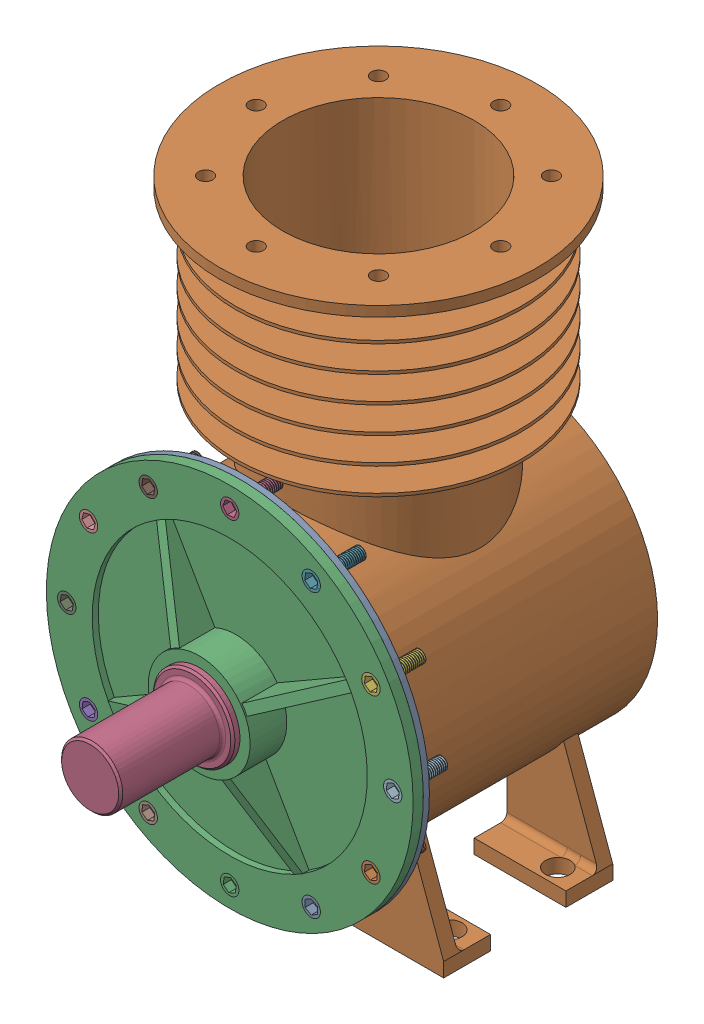
SolidWorks assembly montaj, configuration Varsayılan. Lengths in mm.
Overall size (245.88 307.94 235).
18 component instances, 7 part files, 38 mates.
Components (placement in the parent):
- motor gövdesi-1: motor gövdesi [Varsayılan] at (-13.4199 -2.0149 0) size (180 282 171.5)
- motor kapağı-1: motor kapağı [Varsayılan] at (-13.4199 -2.0149 0) x (-0.866025 -0.5 0) z (0 0 -1) size (180 180 23)
- M6 cıvata-1: M6 cıvata [Varsayılan] at (-13.4199 77.9851 -16) x (0 0 -1) z (0.93131 -0.364228 0) size (24 9 9)
- M6 cıvata-2: M6 cıvata [Varsayılan] at (-82.7019 -42.0149 -16) x (0 0 -1) z (0.991988 -0.126329 0) size (24 9 9)
- M6 cıvata-3: M6 cıvata [Varsayılan] at (55.8621 37.9851 -16) x (0 0 -1) z (0.993619 -0.112785 0) size (24 9 9)
- M6 cıvata-4: M6 cıvata [Varsayılan] at (26.5801 67.2671 -16) x (0 0 -1) z (0.991629 -0.129118 0) size (24 9 9)
- M6 cıvata-5: M6 cıvata [Varsayılan] at (-53.4199 -71.297 -16) x (0 0 -1) z (0.992721 -0.120433 0) size (24 9 9)
- M6 cıvata-6: M6 cıvata [Varsayılan] at (-93.4199 -2.0149 -16) x (0 0 -1) z (0.984484 -0.175472 0) size (24 9 9)
- M6 cıvata-7: M6 cıvata [Varsayılan] at (-82.7019 37.9851 -16) x (0 0 -1) z (0.9652 -0.261513 0) size (24 9 9)
- M6 cıvata-8: M6 cıvata [Varsayılan] at (-53.4199 67.2671 -16) x (0 0 -1) z (0.991366 -0.131123 0) size (24 9 9)
- M6 cıvata-9: M6 cıvata [Varsayılan] at (66.5801 -2.0149 -16) x (0 0 -1) z (0.993166 -0.116712 0) size (24 9 9)
- M6 cıvata-10: M6 cıvata [Varsayılan] at (26.5801 -71.297 -16) x (0 0 -1) z (1 0 0) size (24 9 9)
- M6 cıvata-11: M6 cıvata [Varsayılan] at (55.8621 -42.0149 -16) x (0 0 -1) z (0.995229 -0.097565 0) size (24 9 9)
- M6 cıvata-12: M6 cıvata [Varsayılan] at (-13.4199 -82.0149 -16) x (0 0 -1) z (0.991629 -0.129118 0) size (24 9 9)
- Krank mili-1: Krank mili [Varsayılan] at (-13.4199 -2.0149 -158.5) x (0 0 1) z (0.997767 -0.066787 0) size (235 100 107.84)
- Biyel Kolu-1: Biyel Kolu [Varsayılan] at (-15.4235 -31.948 -63.5) x (0.999793 -0.020331 0) z (0 0 1) size (60 117.55 24)
- perno-1: perno [Varsayılan] at (-13.4199 66.5817 -62) x (0 0 -1) z (0.268596 0.963253 0) size (88 24 24)
- piston-1: piston [Varsayılan] at (-13.4199 76.5817 -65) size (90 70 90)
Mates (geometry in assembly coordinates):
- Çakışık1: coincident anti-aligned: plane of motor gövdesi-1 through (-13.4199 -2.0149 3) normal (0 0 1); plane of motor kapağı-1 through (-49.4199 60.3389 3) normal (0 0 -1)
- Eş Merkezli1: concentric aligned: cylinder of motor gövdesi-1 through (-13.4199 77.9851 -130.001) axis (0 0 1) radius 3; circle of motor kapağı-1
- Eş Merkezli2: concentric aligned: cylinder of motor gövdesi-1 through (-13.4199 -82.0149 -130.001) axis (0 0 1) radius 3; cylinder of motor kapağı-1 through (-13.4199 -82.0149 -0.001) axis (0 0 1) radius 4.5
- Eş Merkezli3: concentric aligned: cylinder of motor gövdesi-1 through (-93.4199 -2.0149 -130.001) axis (0 0 1) radius 3; cylinder of motor kapağı-1 through (-93.4199 -2.0149 -0.001) axis (0 0 1) radius 4.5
- Eş Merkezli4: concentric aligned: cylinder of motor gövdesi-1 through (66.5801 -2.0149 -130.001) axis (0 0 1) radius 3; cylinder of motor kapağı-1 through (66.5801 -2.0149 -0.001) axis (0 0 1) radius 4.5
- Eş Merkezli5: concentric anti-aligned: cylinder of motor kapağı-1 through (-13.4199 77.9851 -0.001) axis (0 0 1) radius 4.5; cylinder of M6 cıvata-1 through (-13.4199 77.9851 -30.4852) axis (0 0 -1) radius 4.5
- Çakışık2: coincident aligned: plane of motor kapağı-1 through (-58.4199 75.9274 8) normal (0 0 1); plane of M6 cıvata-1 through (-11.7809 82.176 8) normal (0 0 1)
- Eş Merkezli6: concentric anti-aligned: cylinder of motor kapağı-1 through (-53.4199 67.2671 -0.001) axis (0 0 1) radius 4.5; cylinder of M6 cıvata-8 through (-53.4199 67.2671 -30.4852) axis (0 0 -1) radius 4.5
- Eş Merkezli7: concentric anti-aligned: cylinder of motor kapağı-1 through (-82.7019 37.9851 -0.001) axis (0 0 1) radius 4.5; cylinder of M6 cıvata-7 through (-82.7019 37.9851 -30.4852) axis (0 0 -1) radius 4.5
- Eş Merkezli8: concentric anti-aligned: cylinder of motor kapağı-1 through (-93.4199 -2.0149 -0.001) axis (0 0 1) radius 4.5; cylinder of M6 cıvata-6 through (-93.4199 -2.0149 -30.4852) axis (0 0 -1) radius 4.5
- Eş Merkezli9: concentric anti-aligned: cylinder of motor kapağı-1 through (-82.7019 -42.0149 -0.001) axis (0 0 1) radius 4.5; cylinder of M6 cıvata-2 through (-82.7019 -42.0149 -30.4852) axis (0 0 -1) radius 4.5
- Eş Merkezli10: concentric anti-aligned: cylinder of motor kapağı-1 through (26.5801 67.2671 -0.001) axis (0 0 1) radius 4.5; cylinder of M6 cıvata-4 through (26.5801 67.2671 -30.4852) axis (0 0 -1) radius 4.5
- Eş Merkezli11: concentric anti-aligned: cylinder of motor kapağı-1 through (55.8621 37.9851 -0.001) axis (0 0 1) radius 4.5; cylinder of M6 cıvata-3 through (55.8621 37.9851 -30.4852) axis (0 0 -1) radius 4.5
- Eş Merkezli12: concentric anti-aligned: cylinder of motor kapağı-1 through (66.5801 -2.0149 -0.001) axis (0 0 1) radius 4.5; cylinder of M6 cıvata-9 through (66.5801 -2.0149 -30.4852) axis (0 0 -1) radius 4.5
- Eş Merkezli13: concentric anti-aligned: cylinder of motor kapağı-1 through (55.8621 -42.0149 -0.001) axis (0 0 1) radius 4.5; cylinder of M6 cıvata-11 through (55.8621 -42.0149 -30.4852) axis (0 0 -1) radius 4.5
- Eş Merkezli14: concentric anti-aligned: cylinder of motor kapağı-1 through (26.5801 -71.297 -0.001) axis (0 0 1) radius 4.5; cylinder of M6 cıvata-10 through (26.5801 -71.297 -30.4852) axis (0 0 -1) radius 4.5
- Eş Merkezli15: concentric anti-aligned: cylinder of motor kapağı-1 through (-53.4199 -71.297 -0.001) axis (0 0 1) radius 4.5; cylinder of M6 cıvata-5 through (-53.4199 -71.297 -30.4852) axis (0 0 -1) radius 4.5
- Çakışık3: coincident aligned: plane of motor kapağı-1 through (-58.4199 75.9274 8) normal (0 0 1); plane of M6 cıvata-8 through (-52.8298 71.7282 8) normal (0 0 1)
- Çakışık4: coincident aligned: plane of motor kapağı-1 through (-58.4199 75.9274 8) normal (0 0 1); plane of M6 cıvata-7 through (-81.5251 42.3285 8) normal (0 0 1)
- Çakışık5: coincident aligned: plane of motor kapağı-1 through (-58.4199 75.9274 8) normal (0 0 1); plane of M6 cıvata-6 through (-92.6303 2.4152 8) normal (0 0 1)
- Çakışık6: coincident aligned: plane of motor kapağı-1 through (-58.4199 75.9274 8) normal (0 0 1); plane of M6 cıvata-2 through (-82.1334 -37.551 8) normal (0 0 1)
- Çakışık7: coincident aligned: plane of motor kapağı-1 through (-58.4199 75.9274 8) normal (0 0 1); plane of M6 cıvata-5 through (-52.8779 -66.8297 8) normal (0 0 1)
- Çakışık8: coincident aligned: plane of motor kapağı-1 through (-58.4199 75.9274 8) normal (0 0 1); plane of M6 cıvata-10 through (26.5801 -66.797 8) normal (0 0 1)
- Çakışık9: coincident aligned: plane of motor kapağı-1 through (-58.4199 75.9274 8) normal (0 0 1); plane of M6 cıvata-11 through (56.3012 -37.5364 8) normal (0 0 1)
- Çakışık10: coincident aligned: plane of motor kapağı-1 through (-58.4199 75.9274 8) normal (0 0 1); plane of M6 cıvata-9 through (67.1053 2.4543 8) normal (0 0 1)
- Çakışık11: coincident aligned: plane of motor kapağı-1 through (-58.4199 75.9274 8) normal (0 0 1); plane of M6 cıvata-3 through (56.3697 42.4564 8) normal (0 0 1)
- Çakışık12: coincident aligned: plane of motor kapağı-1 through (-58.4199 75.9274 8) normal (0 0 1); plane of M6 cıvata-4 through (27.1611 71.7294 8) normal (0 0 1)
- Eş Merkezli16: concentric anti-aligned: cylinder of motor kapağı-1 through (-13.4199 -82.0149 -0.001) axis (0 0 1) radius 4.5; cylinder of M6 cıvata-12 through (-13.4199 -82.0149 -30.4852) axis (0 0 -1) radius 4.5
- Çakışık13: coincident aligned: plane of motor kapağı-1 through (-58.4199 75.9274 8) normal (0 0 1); plane of M6 cıvata-12 through (-12.8389 -77.5526 8) normal (0 0 1)
- Eş Merkezli17: concentric anti-aligned: cylinder of motor kapağı-1 through (-13.4199 -2.0149 0) axis (0 0 1) radius 20; cylinder of Krank mili-1 through (-13.4199 -2.0149 -158.5) axis (0 0 -1) radius 20
- Çakışık15: coincident aligned: plane of motor gövdesi-1 through (-13.4199 -2.0149 -158.5) normal (0 0 -1); plane of Krank mili-1 through (-13.4199 -2.0149 -158.5) normal (0 0 -1)
- Eş Merkezli18: concentric aligned: cylinder of Krank mili-1 through (-15.4235 -31.948 -48.5) axis (0 0 -1) radius 15; cylinder of Biyel Kolu-1 through (-15.4235 -31.948 -51.5) axis (0 0 -1) radius 15
- Uzaklık5: distance = 3 mm anti-aligned: plane of Biyel Kolu-1 through (-15.4235 -31.948 -51.5) normal (0 0 1); plane of Krank mili-1 through (-13.4199 -2.0149 -48.5) normal (0 0 -1)
- Eş Merkezli23: concentric anti-aligned: cylinder of Biyel Kolu-1 through (-13.4199 66.5817 -51.5) axis (0 0 -1) radius 12; cylinder of perno-1 through (-13.4199 66.5817 -18) axis (0 0 1) radius 12
- Eş Merkezli25: concentric anti-aligned: cylinder of Biyel Kolu-1 through (-13.4199 66.5817 -51.5) axis (0 0 -1) radius 12; cylinder of piston-1 through (-13.4199 66.5817 -110) axis (0 0 1) radius 12
- Eş Merkezli26: concentric aligned: cylinder of motor gövdesi-1 through (-13.4199 177.9851 -65) axis (0 -1 0) radius 47; cylinder of piston-1 through (-13.4199 111.5817 -65) axis (0 -1 0) radius 45
- Eş Merkezli27: concentric anti-aligned: cylinder of Biyel Kolu-1 through (-13.4199 66.5817 -51.5) axis (0 0 -1) radius 12; cylinder of perno-1 through (-13.4199 66.5817 -18) axis (0 0 1) radius 12
- Çakışık22: coincident aligned: plane of perno-1 through (-24.9789 69.8048 -106) normal (0 0 -1); circle of piston-1
